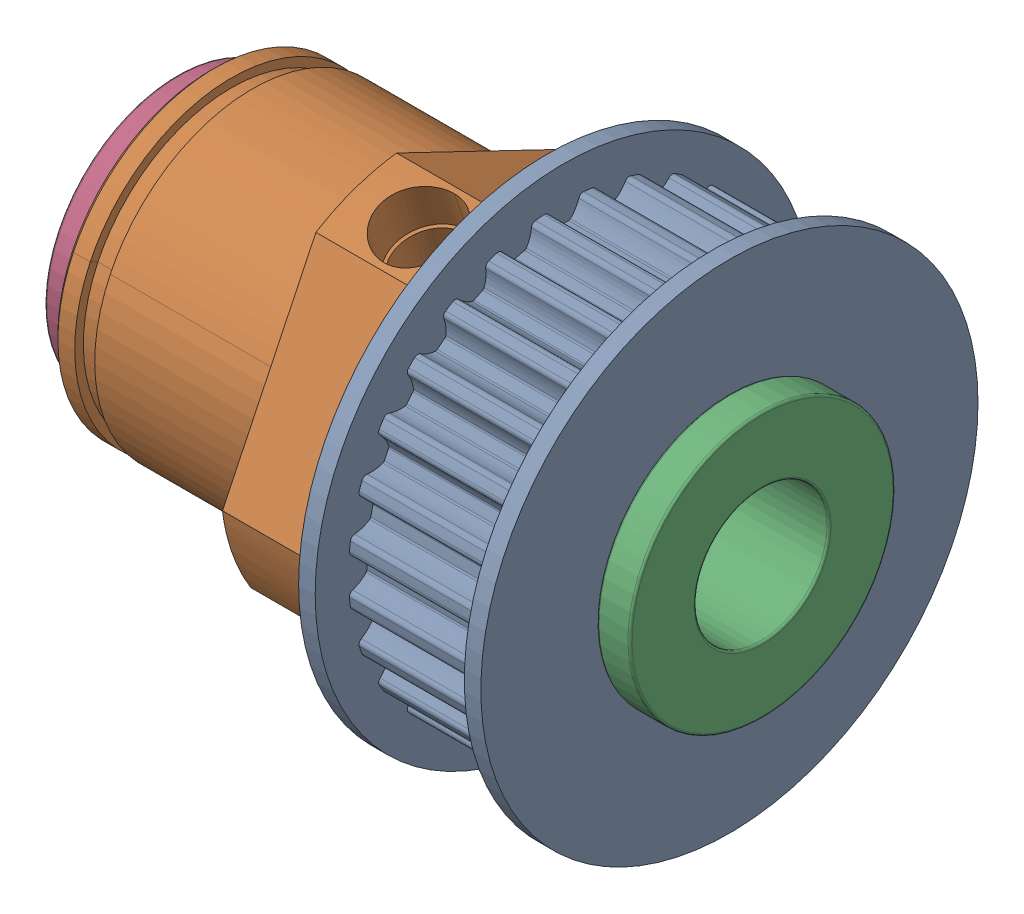
SolidWorks assembly VM-1001-PULLEY-HUB-ASSEMBLY, configuration Default. Lengths in mm.
Overall size (35.32 30 30).
3 component instances, 2 part files, 4 mates.
Components (placement in the parent):
- VM-1002-HUB-PULLEY-1: VM-1002-HUB-PULLEY [Default] at (5.3489 -5.9159 -2.0287) size (31.32 30 30)
- 6659K115_Oil-Embedded Flanged Sleeve Bearing-1: 6659K115_Oil-Embedded Flanged Sleeve Bearing [6659K115] at (14.3835 -4.9141 -1.6722) x (0 -0.721211 0.692716) z (0 -0.692716 -0.721211) size (16 6 16)
- 6659K115_Oil-Embedded Flanged Sleeve Bearing-2: 6659K115_Oil-Embedded Flanged Sleeve Bearing [6659K115] at (-20.9365 -4.9141 -1.6722) x (0 0.98406 -0.177836) z (0 -0.177836 -0.98406) size (16 6 16)
Mates (geometry in assembly coordinates):
- Concentric1: concentric aligned: circle of VM-1002-HUB-PULLEY-1; circle of 6659K115_Oil-Embedded Flanged Sleeve Bearing-2
- Tangent1: tangent: plane of assembly; face of VM-1002-HUB-PULLEY-1; plane of 6659K115_Oil-Embedded Flanged Sleeve Bearing-2 through (-18.9365 -4.9141 -1.6722) normal (1 0 0)
- Concentric3: concentric: cylinder of VM-1002-HUB-PULLEY-1 through (12.3835 -4.9141 -1.6722) axis (-1 0 0) radius 6; cylinder of 6659K115_Oil-Embedded Flanged Sleeve Bearing-1 through (21.1709 -4.9141 -1.6722) axis (1 0 0) radius 4.005
- Coincident2: coincident anti-aligned: plane of VM-1002-HUB-PULLEY-1 through (12.3835 -4.9141 -1.6722) normal (1 0 0); plane of 6659K115_Oil-Embedded Flanged Sleeve Bearing-1 through (12.3835 -4.9141 -1.6722) normal (-1 0 0)
